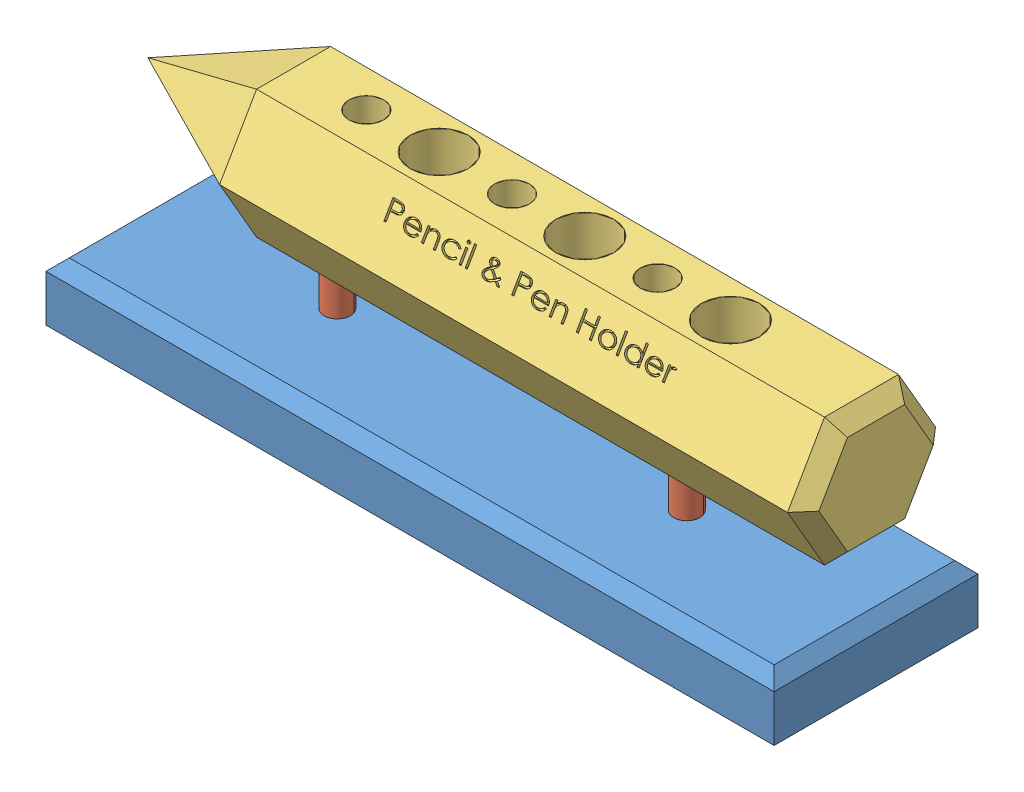
SolidWorks assembly PENCIL & PEN HOLDER, configuration Default. Lengths in mm.
Overall size (250 84 70).
4 component instances, 3 part files, 7 mates.
Components (placement in the parent):
- BASE-1: BASE [Default] at origin size (250 20 70)
- DOWEL-1: DOWEL [Default] at (185 10 -35) size (9 50 9)
- DOWEL-2: DOWEL [Default] at (65 10 -35) size (9 50 9)
- PEN HOLDER-1: PEN HOLDER [Default] at (250 62 -35) x (0 0 1) z (-1 0 0) size (50.81 44 250)
Mates (geometry in assembly coordinates):
- Concentric1: concentric anti-aligned: cylinder of BASE-1 through (65 10 -35) axis (0 1 0) radius 4.5; cylinder of DOWEL-2 through (65 60 -35) axis (0 -1 0) radius 4.5
- Coincident1: coincident anti-aligned: plane of BASE-1 through (65 10 -35) normal (0 1 0); plane of DOWEL-2 through (65 10 -35) normal (0 -1 0)
- Concentric2: concentric anti-aligned: cylinder of BASE-1 through (185 10 -35) axis (0 1 0) radius 4.5; cylinder of DOWEL-1 through (185 60 -35) axis (0 -1 0) radius 4.5
- Coincident2: coincident anti-aligned: plane of BASE-1 through (185 10 -35) normal (0 1 0); plane of DOWEL-1 through (185 10 -35) normal (0 -1 0)
- Concentric3: concentric aligned: cylinder of DOWEL-1 through (185 60 -35) axis (0 -1 0) radius 4.5; cylinder of PEN HOLDER-1 through (185 60 -35) axis (0 -1 0) radius 4.5
- Concentric4: concentric aligned: cylinder of DOWEL-2 through (65 60 -35) axis (0 -1 0) radius 4.5; cylinder of PEN HOLDER-1 through (65 60 -35) axis (0 -1 0) radius 4.5
- Coincident3: coincident anti-aligned: circle of DOWEL-1; circle of PEN HOLDER-1
